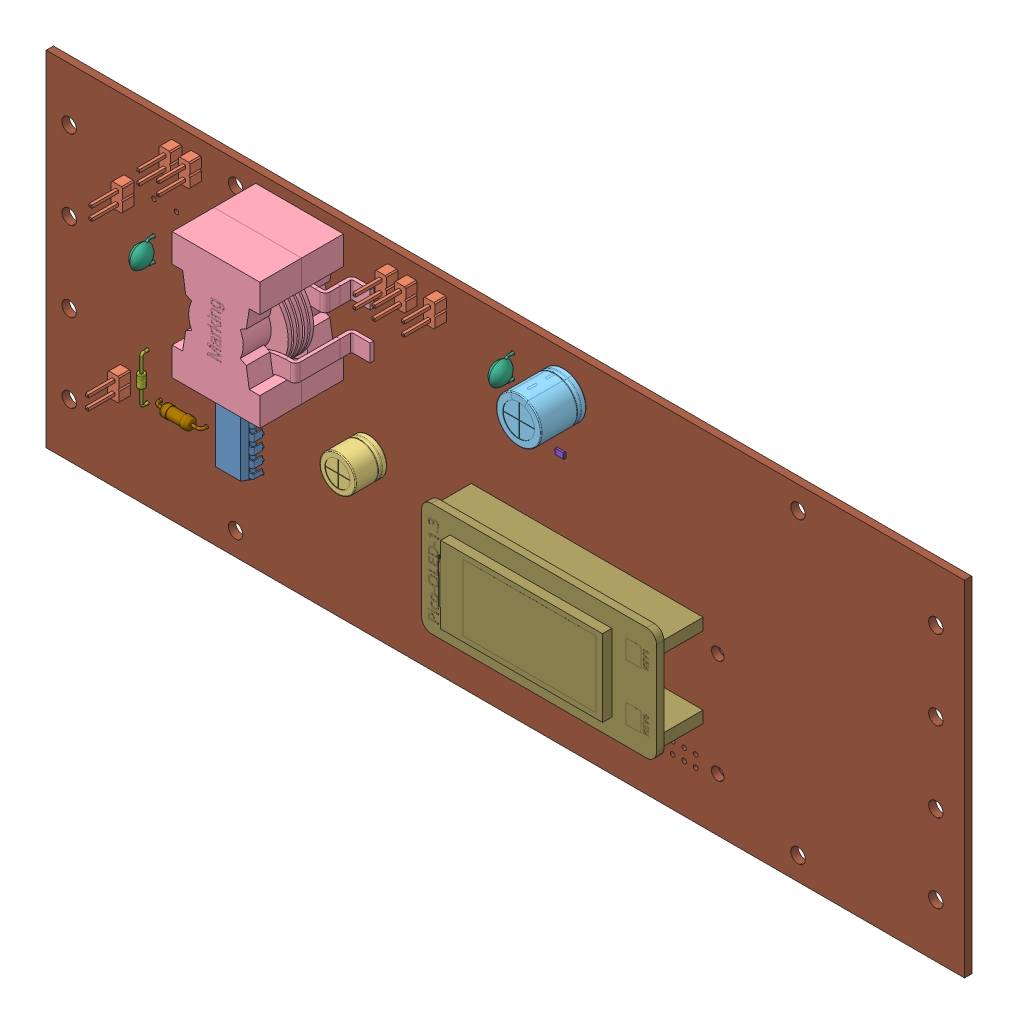
SolidWorks assembly pcb assembly, configuration Default. Lengths in mm.
Overall size (203.2 76.2 25.48).
38 component instances, 13 part files, 5 mates.
Components (placement in the parent):
- PCBbigboard.STEP-1: PCBbigboard.STEP [Default] at (-38.2916 134.4406 161.2796) size (203.2 76.2 25.05)
  - DIP-16_W7.62mm.STEP-1: DIP-16_W7.62mm.STEP [Default] at (40.1678 -39.2834 1.65) size (7.87 19.18 6.98)
    - SOLID.STEP-1: SOLID.STEP [Default] at origin size (7.87 19.18 6.98)
  - PinHeader_1x02_P2.54mm_Vertical.STEP-1: PinHeader_1x02_P2.54mm_Vertical.STEP [Default] at (18.2372 -19.05 1.65) x (-1 0 0) z (0 0 1) size (2.54 5.08 11.54)
    - SOLID-0.STEP-1: SOLID-0.STEP [Default] at origin size (2.54 5.08 11.54)
  - C_Radial_D8.0mm_H7.0mm_P3.50mm.STEP-1: C_Radial_D8.0mm_H7.0mm_P3.50mm.STEP [Default] at (73.2687 -41.8846 1.65) x (-1 0 0) z (0 0 1) size (10.06 10.93 9)
    - SOLID-1.STEP-1: SOLID-1.STEP [Default] at origin size (10.06 10.93 9)
  - PinHeader_1x02_P2.54mm_Vertical.STEP-2: PinHeader_1x02_P2.54mm_Vertical.STEP [Default] at (33.0962 -4.3892 1.65) size (2.54 5.08 11.54)
    - SOLID-0.STEP-1: SOLID-0.STEP [Default] at origin size (2.54 5.08 11.54)
  - 7443640330_Download_STP_WE-HCF-2818_rev1.STEP-1: 7443640330_Download_STP_WE-HCF-2818_rev1.STEP [Default] at (56.382 -16.002 11.175) x (0 1 0) z (0 0 1) size (28 27.81 18.55)
    - COMPOUND.STEP-1: COMPOUND.STEP [Default] at origin size (28 27.81 18.55)
  - PinHeader_1x02_P2.54mm_Vertical.STEP-3: PinHeader_1x02_P2.54mm_Vertical.STEP [Default] at (87.3506 -4.1402 1.65) size (2.54 5.08 11.54)
    - SOLID-0.STEP-1: SOLID-0.STEP [Default] at origin size (2.54 5.08 11.54)
  - PinHeader_1x02_P2.54mm_Vertical.STEP-4: PinHeader_1x02_P2.54mm_Vertical.STEP [Default] at (17.4498 -55.7784 1.65) x (-1 0 0) z (0 0 1) size (2.54 5.08 11.54)
    - SOLID-0.STEP-1: SOLID-0.STEP [Default] at origin size (2.54 5.08 11.54)
  - PinHeader_1x02_P2.54mm_Vertical.STEP-5: PinHeader_1x02_P2.54mm_Vertical.STEP [Default] at (28.8036 -4.4146 1.65) size (2.54 5.08 11.54)
    - SOLID-0.STEP-1: SOLID-0.STEP [Default] at origin size (2.54 5.08 11.54)
  - CP_Radial_D10.0mm_P5.00mm.STEP-1: CP_Radial_D10.0mm_P5.00mm.STEP [Default] at (114.5794 -11.1307 1.65) x (0 1 0) z (0 0 1) size (12.36 12.78 12)
    - SOLID-2.STEP-1: SOLID-2.STEP [Default] at origin size (12.36 12.78 12)
  - C_Disc_D5.1mm_W3.2mm_P5.00mm.STEP-1: C_Disc_D5.1mm_W3.2mm_P5.00mm.STEP [Default] at (23.749 -28.702 1.65) x (0 1 0) z (0 0 1) size (6 3.2 7.2)
    - SOLID-3.STEP-1: SOLID-3.STEP [Default] at origin size (6 3.2 7.2)
  - D_DO-34_SOD68_P10.16mm_Horizontal.STEP-1: D_DO-34_SOD68_P10.16mm_Horizontal.STEP [Default] at (22.4282 -46.2026 1.65) x (0 -1 0) z (0 0 1) size (10.71 1.61 4.6)
    - SOLID-4.STEP-1: SOLID-4.STEP [Default] at origin size (10.71 1.61 4.6)
  - R_0805_2012Metric.STEP-1: R_0805_2012Metric.STEP [Default] at (114.046 -20.066 1.65) size (2 1.2 0.45)
    - SOLID-5.STEP-1: SOLID-5.STEP [Default] at origin size (2 1.2 0.45)
  - PinHeader_1x02_P2.54mm_Vertical.STEP-6: PinHeader_1x02_P2.54mm_Vertical.STEP [Default] at (80.8736 -4.3688 1.65) size (2.54 5.08 11.54)
    - SOLID-0.STEP-1: SOLID-0.STEP [Default] at origin size (2.54 5.08 11.54)
  - C_Disc_D5.1mm_W3.2mm_P5.00mm.STEP-2: C_Disc_D5.1mm_W3.2mm_P5.00mm.STEP [Default] at (103.251 -6.39 1.65) x (0 -1 0) z (0 0 1) size (6 3.2 7.2)
    - SOLID-3.STEP-1: SOLID-3.STEP [Default] at origin size (6 3.2 7.2)
  - PinHeader_1x02_P2.54mm_Vertical.STEP-7: PinHeader_1x02_P2.54mm_Vertical.STEP [Default] at (76.581 -4.3688 1.65) size (2.54 5.08 11.54)
    - SOLID-0.STEP-1: SOLID-0.STEP [Default] at origin size (2.54 5.08 11.54)
  - R_Axial_DIN0207_L6.3mm_D2.5mm_P10.16mm_Horizontal.STEP-1: R_Axial_DIN0207_L6.3mm_D2.5mm_P10.16mm_Horizontal.STEP [Default] at (35.5346 -54.3814 1.65) x (-1 0 0) z (0 0 1) size (10.76 2.5 5.5)
    - SOLID-6.STEP-1: SOLID-6.STEP [Default] at origin size (10.76 2.5 5.5)
  - KTW0007B.STEP-1: KTW0007B.STEP [Default] at (80.3656 -33.0073 -0.05) x (1 0 0) z (0 1 0) size (10.16 4.72 14.3)
    - COMPOUND-7.STEP-1: COMPOUND-7.STEP [Default] at origin size (10.16 4.72 14.3)
  - PCB.STEP-1: PCB.STEP [Default] at origin size (203.2 76.2 1.6)
- Pico-OLED-1.3.step-1: Pico-OLED-1.3.step [Default] at (107.4054 100.8631 173.5296) x (-1 0 0) z (0 0 1) size (52 25 12.76)
- Raspberry Pi Zero 2 W-1: Raspberry Pi Zero 2 W [Default] at (81.2916 81.577 160.4796) x (1 0 0) z (0 1 0) size (65.8 5.05 30.58)
Mates (geometry in assembly coordinates):
- Coincident2: coincident anti-aligned: plane of PCBbigboard.STEP-1/PCB.STEP-1 through (63.3084 96.3406 162.8796) normal (0 0 1); plane of Pico-OLED-1.3.step-1 through (81.4054 88.3631 162.8796) normal (0 0 -1)
- Parallel2: parallel aligned: line of PCBbigboard.STEP-1/PCB.STEP-1 through (164.9084 134.4406 162.8796) axis (0 -1 0); line of Pico-OLED-1.3.step-1 through (55.4054 98.6631 173.5296) axis (0 -1 0)
- Coincident5: coincident: plane of PCBbigboard.STEP-1/PCB.STEP-1 through (63.3084 96.3406 161.2796) normal (0 0 -1); plane of Raspberry Pi Zero 2 W-1 through (82.3848 78.3019 161.2796) normal (0 0 1)
- Concentric1: concentric: circle of PCBbigboard.STEP-1/PCB.STEP-1; circle of Raspberry Pi Zero 2 W-1
- Concentric2: concentric aligned: circle of PCBbigboard.STEP-1/PCB.STEP-1; circle of Raspberry Pi Zero 2 W-1
